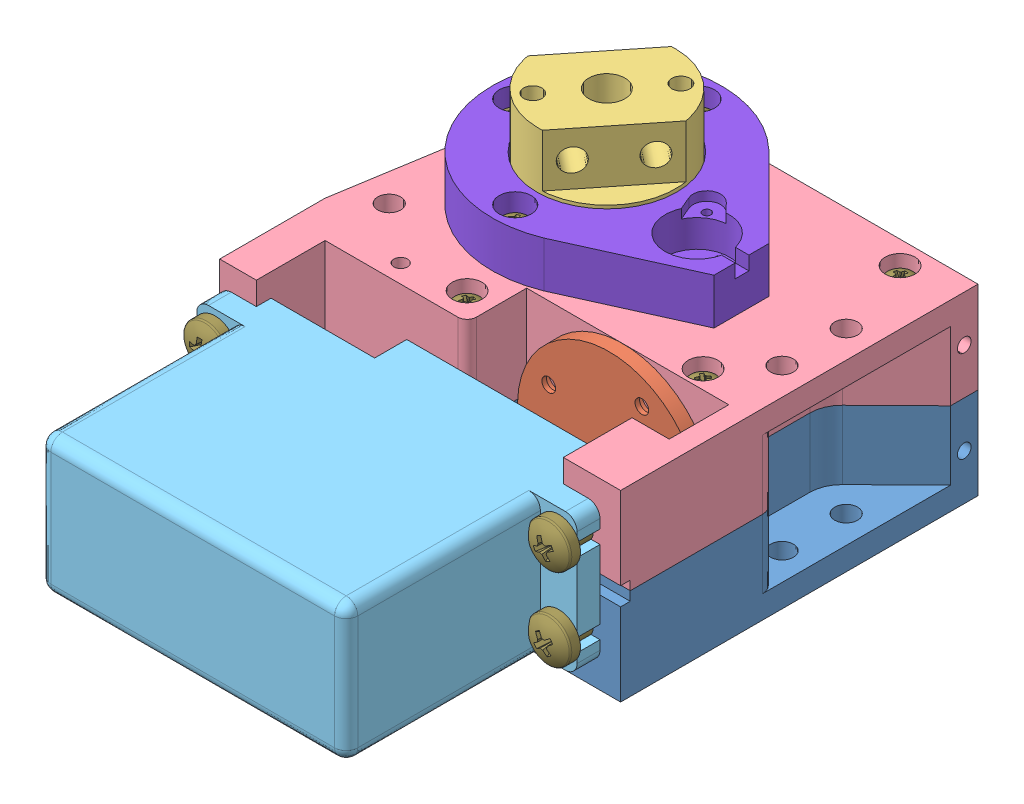
SolidWorks assembly large gearbox mirror, configuration Default. Lengths in mm.
Overall size (90.22 74 134.56).
28 component instances, 12 part files, 58 mates.
Components (placement in the parent):
- bottom housing mirror-1: bottom housing mirror [Default] at (7.4002 -24.2748 -89.7718) x (1 0 0) z (0 -1 0) size (87.5 78 20)
- wormscrew-1: wormscrew [Default] at (21.4002 -4.2748 -75.7718) x (-0.47589 -0.879505 0) z (0 0 -1) size (40 40 51)
- driveshaft cog-1: driveshaft cog [Default] at (-6.5998 -9.2748 -103.2718) x (0.623441 0 -0.78187) z (0 1 0) size (49.29 49.31 47)
- top housing mirror-1: top housing mirror [Default] at (-6.5998 15.7252 -103.2718) x (-1 0 0) z (0 1 0) size (87.5 78 40)
- HS-805BB-1: HS-805BB [Default] at (2.9002 -19.2748 -28.6693) x (1 0 0) z (0 1 0) size (83 68.8 30)
- 608ZZ-1: 608ZZ [Default] at (21.4002 -4.2748 -127.5718) x (0.996867 0.079098 0) z (0 0 1) size (22 22 7)
- 6806 30x42x7-1: 6806 30x42x7 [Default] at (-6.5998 -22.2748 -103.2718) x (0.979879 0 -0.199591) z (0 1 0) size (42 42 7)
- 6806 30x42x7-2: 6806 30x42x7 [Default] at (-6.5998 9.7252 -103.2718) x (0.968497 0 -0.249026) z (0 -1 0) size (42 42 7)
- pot holder mirror-1: pot holder mirror [Default] at (-6.5998 15.7252 -103.2718) x (0 0 1) z (0 -1 0) size (50 60 10)
- cog brace-1: cog brace [Default] at (18.6002 9.7252 -104.6718) x (1 0 0) z (0 -1 0) size (8.5 22.65 3)
- pot cog-1: pot cog [Default] at (18.6002 12.7252 -97.7718) x (0.51355 0 -0.85806) z (0 -1 0) size (28 27.88 7.9)
- driveshaft-1: driveshaft [Default] at (-6.5998 -9.2748 -103.2718) x (-0.623441 0 0.78187) z (0 -1 0) size (36.44 35.48 27)
- Pan Head Cross Recess Screw_ISO-1: Pan Head Cross Recess Screw_ISO [ISO 7045 - M3 x 10 - Z --- 10N] at (-26.5998 23.1252 -103.2718) x (0 -1 0) z (0 0 -1) size (12.35 5.6 5.6)
- Pan Head Cross Recess Screw_ISO-2: Pan Head Cross Recess Screw_ISO [ISO 7045 - M3 x 10 - Z --- 10N] at (-6.5998 23.1252 -123.2718) x (0 -1 0) z (0.495758 0 -0.868461) size (12.35 5.6 5.6)
- Pan Head Cross Recess Screw_ISO-3: Pan Head Cross Recess Screw_ISO [ISO 7045 - M3 x 10 - Z --- 10N] at (-6.5998 23.1252 -83.2718) x (0 -1 0) z (0.927545 0 -0.373711) size (12.35 5.6 5.6)
- Pan Head Cross Recess Screw_ISO-4: Pan Head Cross Recess Screw_ISO [ISO 7045 - M5 x 12 - Z --- 12N] at (-34.5998 -13.2748 -42.0718) x (0 0 -1) z (-1 0 0) size (15.63 9.5 9.5)
- Pan Head Cross Recess Screw_ISO-5: Pan Head Cross Recess Screw_ISO [ISO 7045 - M5 x 12 - Z --- 12N] at (-34.5998 4.7252 -42.0718) x (0 0 -1) z (-1 0 0) size (15.63 9.5 9.5)
- Pan Head Cross Recess Screw_ISO-6: Pan Head Cross Recess Screw_ISO [ISO 7045 - M3 x 30 - Z --- 25N] at (-27.0895 14.1252 -123.7718) x (0 -1 0) z (0 0 -1) size (32.35 5.6 5.6)
- Pan Head Cross Recess Screw_ISO-7: Pan Head Cross Recess Screw_ISO [ISO 7045 - M3 x 30 - Z --- 25N] at (-18.0998 -22.6748 -69.7718) x (0 1 0) z (0 0 -1) size (32.35 5.6 5.6)
- Pan Head Cross Recess Screw_ISO-8: Pan Head Cross Recess Screw_ISO [ISO 7045 - M3 x 30 - Z --- 25N] at (34.9002 14.1252 -82.7718) x (0 -1 0) z (-0.8218 0 -0.569776) size (32.35 5.6 5.6)
- Pan Head Cross Recess Screw_ISO-9: Pan Head Cross Recess Screw_ISO [ISO 7045 - M3 x 30 - Z --- 25N] at (-5.5998 14.1252 -71.7718) x (0 -1 0) z (0.38373 0 -0.923445) size (32.35 5.6 5.6)
- Pan Head Cross Recess Screw_ISO-10: Pan Head Cross Recess Screw_ISO [ISO 7045 - M2 x 6 - Z --- 6N] at (18.6002 6.6252 -115.2718) x (0 1 0) z (0.855583 0 0.517665) size (7.57 4 4)
- Pan Head Cross Recess Screw_ISO-11: Pan Head Cross Recess Screw_ISO [ISO 7045 - M3 x 5 - Z --- 5N] at (-19.8916 -13.6748 -113.8703) x (0 1 0) z (0.934817 0 -0.355129) size (7.35 5.6 5.6)
- Pan Head Cross Recess Screw_ISO-12: Pan Head Cross Recess Screw_ISO [ISO 7045 - M3 x 5 - Z --- 5N] at (9.2246 -13.6748 -109.4836) x (0 1 0) z (-0.000145 0 -1) size (7.35 5.6 5.6)
- Pan Head Cross Recess Screw_ISO-13: Pan Head Cross Recess Screw_ISO [ISO 7045 - M3 x 5 - Z --- 5N] at (-9.1325 -13.6748 -86.4615) x (0 1 0) z (-0.12044 0 -0.992721) size (7.35 5.6 5.6)
- Pan Head Cross Recess Screw_ISO-14: Pan Head Cross Recess Screw_ISO [ISO 7045 - M3 x 30 - Z --- 25N] at (36.9002 14.1252 -123.7718) x (0 -1 0) z (0.993717 0 0.111922) size (32.35 5.6 5.6)
- Pan Head Cross Recess Screw_ISO-15: Pan Head Cross Recess Screw_ISO [ISO 7045 - M5 x 12 - Z --- 12N] at (40.4002 4.7252 -42.0718) x (0 0 -1) z (0.445798 -0.895134 0) size (15.63 9.5 9.5)
- Pan Head Cross Recess Screw_ISO-16: Pan Head Cross Recess Screw_ISO [ISO 7045 - M5 x 12 - Z --- 12N] at (40.4002 -13.2748 -42.0718) x (0 0 -1) z (0.583619 -0.812027 0) size (15.63 9.5 9.5)
Mates (geometry in assembly coordinates):
- Coincident1: coincident anti-aligned: plane of bottom housing mirror-1 through (-34.0998 -4.2748 -50.7718) normal (0 0 1); plane of HS-805BB-1 through (-38.5998 10.7252 -50.7718) normal (0 0 -1)
- Concentric1: concentric aligned: circle of wormscrew-1; circle of HS-805BB-1
- Coincident2: coincident anti-aligned: plane of bottom housing mirror-1 through (36.4002 11.2494 -65.7718) normal (-1 0 0); plane of HS-805BB-1 through (36.4002 10.7252 -50.7718) normal (1 0 0)
- Coincident3: coincident anti-aligned: plane of bottom housing mirror-1 through (32.6502 -15.4748 -127.5718) normal (0 0 1); plane of 608ZZ-1 through (21.4002 -4.2748 -127.5718) normal (0 0 -1)
- Coincident4: coincident anti-aligned: plane of bottom housing mirror-1 through (-6.5998 -22.2748 -103.2718) normal (0 1 0); plane of 6806 30x42x7-1 through (-6.5998 -22.2748 -103.2718) normal (0 -1 0)
- Concentric2: concentric anti-aligned: cylinder of bottom housing mirror-1; cylinder of 6806 30x42x7-1
- Coincident5: coincident anti-aligned: plane of driveshaft cog-1 through (-6.5998 2.7252 -103.2718) normal (0 1 0); plane of 6806 30x42x7-2 through (-6.5998 2.7252 -103.2718) normal (0 -1 0)
- Concentric4: concentric anti-aligned: cylinder of HS-805BB-1; cylinder of Pan Head Cross Recess Screw_ISO-15
- Coincident6: coincident anti-aligned: plane of HS-805BB-1 through (36.4002 10.7252 -45.7718) normal (0 0 1); plane of Pan Head Cross Recess Screw_ISO-15 through (42.638 5.8397 -45.7718) normal (0 0 -1)
- Concentric5: concentric anti-aligned: cylinder of HS-805BB-1; cylinder of Pan Head Cross Recess Screw_ISO-16
- Coincident7: coincident anti-aligned: plane of HS-805BB-1 through (36.4002 10.7252 -45.7718) normal (0 0 1); plane of Pan Head Cross Recess Screw_ISO-16 through (42.4302 -11.8157 -45.7718) normal (0 0 -1)
- Concentric6: concentric anti-aligned: cylinder of HS-805BB-1; cylinder of Pan Head Cross Recess Screw_ISO-4
- Coincident8: coincident anti-aligned: plane of HS-805BB-1 through (-30.5998 10.7252 -45.7718) normal (0 0 1); plane of Pan Head Cross Recess Screw_ISO-4 through (-34.5998 -15.7748 -45.7718) normal (0 0 -1)
- Concentric7: concentric anti-aligned: cylinder of HS-805BB-1; cylinder of Pan Head Cross Recess Screw_ISO-5
- Coincident9: coincident anti-aligned: plane of HS-805BB-1 through (-30.5998 10.7252 -45.7718) normal (0 0 1); plane of Pan Head Cross Recess Screw_ISO-5 through (-34.5998 2.2252 -45.7718) normal (0 0 -1)
- Coincident10: coincident anti-aligned: plane of bottom housing mirror-1 through (-18.0998 -20.2748 -69.7718) normal (0 -1 0); plane of Pan Head Cross Recess Screw_ISO-7 through (-16.5998 -20.2748 -69.7718) normal (0 1 0)
- Coincident11: coincident anti-aligned: plane of cog brace-1 through (23.1002 8.2252 -111.6718) normal (0 -1 0); plane of Pan Head Cross Recess Screw_ISO-10 through (18.0825 8.2252 -114.4162) normal (0 1 0)
- Concentric8: concentric aligned: cylinder of driveshaft cog-1; cylinder of Pan Head Cross Recess Screw_ISO-11
- Concentric9: concentric anti-aligned: cylinder of pot holder mirror-1; cylinder of Pan Head Cross Recess Screw_ISO-2
- Coincident12: coincident anti-aligned: plane of pot holder mirror-1 through (-6.5998 20.7252 -123.2718) normal (0 1 0); plane of Pan Head Cross Recess Screw_ISO-2 through (-7.9025 20.7252 -124.0154) normal (0 -1 0)
- Concentric10: concentric anti-aligned: cylinder of pot holder mirror-1; cylinder of Pan Head Cross Recess Screw_ISO-3
- Coincident13: coincident anti-aligned: plane of pot holder mirror-1 through (-6.5998 20.7252 -83.2718) normal (0 1 0); plane of Pan Head Cross Recess Screw_ISO-3 through (-7.1604 20.7252 -84.6631) normal (0 -1 0)
- Coincident14: coincident anti-aligned: plane of pot holder mirror-1 through (-26.5998 20.7252 -103.2718) normal (0 1 0); plane of Pan Head Cross Recess Screw_ISO-1 through (-28.0998 20.7252 -103.2718) normal (0 -1 0)
- Concentric11: concentric anti-aligned: cylinder of pot holder mirror-1; cylinder of Pan Head Cross Recess Screw_ISO-1
- GearMate1: gear = 0.001 : 0.013: circle of driveshaft cog-1; circle of wormscrew-1
- GearMate2: gear = 0.001 : 0.001: circle of pot cog-1; circle of driveshaft cog-1
- Coincident16: coincident aligned: plane of top housing mirror-1 through (-6.5998 9.7252 -103.2718) normal (0 -1 0); circle of 6806 30x42x7-2
- Concentric13: concentric anti-aligned: cylinder of top housing mirror-1; cylinder of 6806 30x42x7-2
- Concentric14: concentric anti-aligned: cylinder of driveshaft cog-1; cylinder of top housing mirror-1
- Coincident17: coincident anti-aligned: plane of top housing mirror-1 through (18.6002 12.7252 -97.7718) normal (0 -1 0); plane of pot cog-1 through (20.5571 12.7252 -91.7908) normal (0 1 0)
- Concentric16: concentric aligned: circle of cog brace-1; cylinder of Pan Head Cross Recess Screw_ISO-10
- Concentric17: concentric aligned: cylinder of top housing mirror-1; cylinder of Pan Head Cross Recess Screw_ISO-10
- Coincident19: coincident anti-aligned: plane of top housing mirror-1 through (23.1002 9.7252 -108.9666) normal (0 -1 0); plane of cog brace-1 through (20.8502 9.7252 -97.6718) normal (0 1 0)
- Concentric19: concentric anti-aligned: circle of driveshaft cog-1; circle of driveshaft-1
- Coincident22: coincident aligned: cylinder of driveshaft cog-1; circle of driveshaft-1
- Coincident23: coincident anti-aligned: plane of Pan Head Cross Recess Screw_ISO-11 through (-19.3589 -11.2748 -112.4681) normal (0 1 0); plane of driveshaft-1 through (-19.8916 -11.2748 -113.8703) normal (0 -1 0)
- Coincident24: coincident anti-aligned: plane of driveshaft cog-1 through (-6.5998 -9.2748 -103.2718) normal (0 -1 0); plane of driveshaft-1 through (-6.5998 -9.2748 -103.2718) normal (0 1 0)
- Coincident25: coincident aligned: circle of driveshaft-1; cylinder of Pan Head Cross Recess Screw_ISO-12
- Coincident26: coincident aligned: plane of driveshaft-1 through (9.2246 -11.2748 -109.4836) normal (0 -1 0); circle of Pan Head Cross Recess Screw_ISO-12
- Coincident27: coincident aligned: circle of driveshaft-1; cylinder of Pan Head Cross Recess Screw_ISO-13
- Coincident28: coincident aligned: plane of driveshaft-1 through (-9.1325 -11.2748 -86.4615) normal (0 -1 0); circle of Pan Head Cross Recess Screw_ISO-13
- Concentric23: concentric aligned: circle of top housing mirror-1; cylinder of 608ZZ-1
- Coincident29: coincident anti-aligned: plane of top housing mirror-1 through (32.6502 7.2252 -127.5718) normal (0 0 1); plane of 608ZZ-1 through (21.4002 -4.2748 -127.5718) normal (0 0 -1)
- Concentric24: concentric anti-aligned: cylinder of wormscrew-1; cylinder of top housing mirror-1
- Coincident31: coincident anti-aligned: plane of wormscrew-1 through (21.4002 -4.2748 -78.7718) normal (0 0 -1); plane of top housing mirror-1 through (0.4002 -4.2748 -78.7718) normal (0 0 1)
- Coincident32: coincident anti-aligned: circle of bottom housing mirror-1; cylinder of Pan Head Cross Recess Screw_ISO-6
- Concentric25: concentric aligned: cylinder of top housing mirror-1; cylinder of Pan Head Cross Recess Screw_ISO-6
- Coincident33: coincident anti-aligned: plane of top housing mirror-1 through (-28.7895 11.7252 -123.7718) normal (0 1 0); plane of Pan Head Cross Recess Screw_ISO-6 through (-28.5895 11.7252 -123.7718) normal (0 -1 0)
- Coincident34: coincident anti-aligned: plane of bottom housing mirror-1 through (-34.0998 -4.2748 -128.7718) normal (0 1 0); plane of top housing mirror-1 through (-1.5998 -4.2748 -67.7718) normal (0 -1 0)
- Concentric26: concentric anti-aligned: circle of top housing mirror-1; circle of Pan Head Cross Recess Screw_ISO-9
- Coincident35: coincident aligned: plane of top housing mirror-1 through (-7.2998 11.7252 -71.7718) normal (0 1 0); circle of Pan Head Cross Recess Screw_ISO-9
- Concentric27: concentric anti-aligned: circle of top housing mirror-1; cylinder of Pan Head Cross Recess Screw_ISO-8
- Coincident36: coincident aligned: plane of top housing mirror-1 through (33.2002 11.7252 -82.7718) normal (0 1 0); circle of Pan Head Cross Recess Screw_ISO-8
- Concentric28: concentric anti-aligned: circle of top housing mirror-1; circle of Pan Head Cross Recess Screw_ISO-14
- Coincident37: coincident anti-aligned: plane of top housing mirror-1 through (35.2002 11.7252 -123.7718) normal (0 1 0); plane of Pan Head Cross Recess Screw_ISO-14 through (37.068 11.7252 -125.2624) normal (0 -1 0)
- Concentric29: concentric anti-aligned: cylinder of driveshaft cog-1; cylinder of pot holder mirror-1
- Coincident38: coincident anti-aligned: plane of top housing mirror-1 through (-1.5998 15.7252 -67.7718) normal (0 1 0); plane of pot holder mirror-1 through (-6.5998 15.7252 -103.2718) normal (0 -1 0)
- Concentric30: concentric anti-aligned: cylinder of top housing mirror-1; circle of pot holder mirror-1
